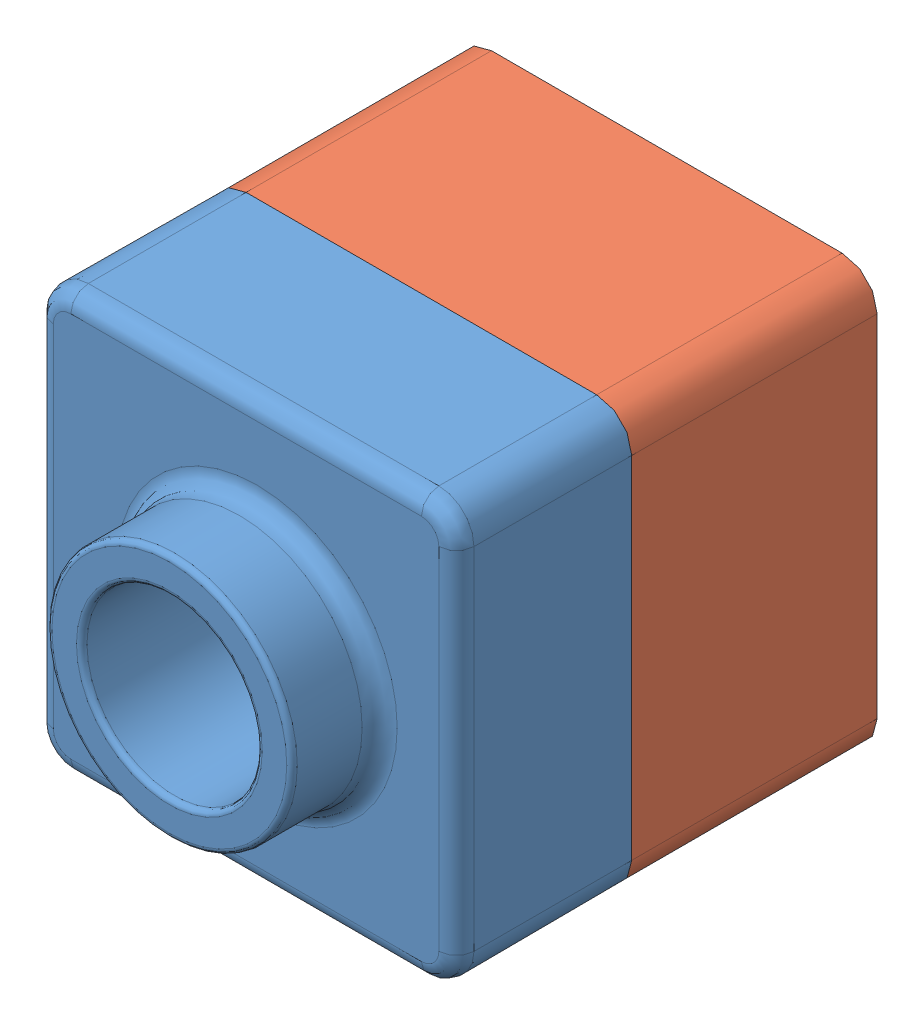
SolidWorks assembly Tutor, configuration Default. Lengths in mm.
Overall size (120 120 145).
2 component instances, 2 part files, 3 mates.
Components (placement in the parent):
- Tutor1-1: Tutor1 [Default] at (-39.5059 37.9121 153.3815) size (120 120 75)
- Tutor2-1: Tutor2 [Default] at (-39.5059 37.9121 83.3815) size (120 120 90)
Mates (geometry in assembly coordinates):
- Coincident1: coincident: plane of Tutor1-1 through (-39.5059 37.9121 153.3815) normal (0 0 -1); plane of Tutor2-1 through (-278.1743 147.9121 153.3815) normal (0 0 1)
- Coincident2: coincident: plane of Tutor1-1 through (-39.5059 37.9121 203.3815) normal (0 -1 0); plane of Tutor2-1 through (-288.1743 37.9121 173.3815) normal (0 -1 0)
- Coincident7: coincident aligned: plane of Tutor1-1 through (80.4941 37.9121 203.3815) normal (1 0 0); plane of Tutor2-1 through (80.4941 37.9121 173.3815) normal (1 0 0)
